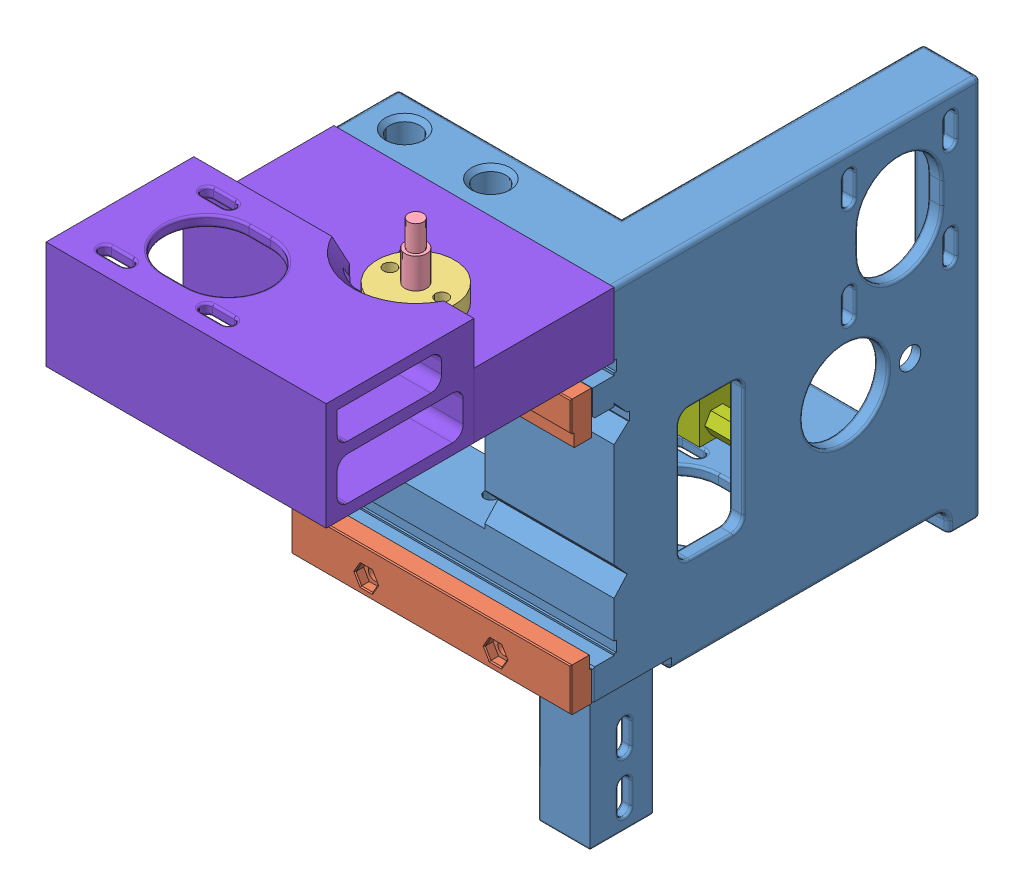
SolidWorks assembly back_carrent_assebly, configuration Default. Lengths in mm.
Overall size (142.93 256 310.81).
9 component instances, 8 part files, 25 mates.
Components (placement in the parent):
- back_integrated-1: back_integrated [Default] at (105.0761 55.2027 88.3003) size (142.93 222 230)
- line_plastic-1: line_plastic [Default] at (184.8997 30.5335 118.1123) x (0 -1 0) z (-1 0 0) size (20 10 130)
- line_plastic-2: line_plastic [Default] at (184.8997 117.3461 148.4883) x (0 1 0) z (-1 0 0) size (20 10 130)
- root_hosder-1: root_hosder [Default] at (144.8997 180.5335 170.3003) x (0.419128 0 -0.907927) z (0 -1 0) size (36 36 28)
- s2-1: s2 [Default] at (144.8997 142.5335 170.3003) x (0.905157 0 0.425078) z (-0.425078 0 0.905157) size (16 64 16)
- key-1: key [Default] at (139.4688 188.0525 167.7498) x (0 1 0) z (0.905157 0 0.425078) size (10 4 6)
- small_sensor-1: small_sensor [Default] at (146.4207 152.5335 148.3003) x (0 -0.945736 0.324935) z (-1 0 0) size (8 8 51)
- injector-1: injector [Default] at (150.9398 10.5335 15.061) x (1 0 0) z (0 1 0) size (75.8 59.7 24.9)
- back_integrated - Copy-1: back_integrated - Copy [Default] at (106.6103 24.7727 88.3003) size (130 50.09 133.58)
Mates (geometry in assembly coordinates):
- Совпадение1: coincident anti-aligned: plane of back_integrated-1 through (105.0761 55.2027 128.3003) normal (0 0 1); plane of line_plastic-1 through (54.8997 30.5335 128.3003) normal (0 0 -1)
- Совпадение2: coincident aligned: plane of back_integrated-1 through (54.8997 10.5335 118.3003) normal (0 -1 0); plane of line_plastic-1 through (54.8997 10.5335 128.3003) normal (0 -1 0)
- Совпадение3: coincident aligned: plane of back_integrated-1 through (184.8997 172.5335 118.3003) normal (1 0 0); plane of line_plastic-1 through (184.8997 30.5335 118.1123) normal (1 0 0)
- Совпадение4: coincident anti-aligned: plane of back_integrated-1 through (105.0761 55.2027 128.3003) normal (0 0 1); plane of line_plastic-2 through (54.8997 137.3461 128.3003) normal (0 0 -1)
- Совпадение5: coincident: plane of back_integrated-1 through (184.8997 137.0335 128.3003) normal (0 1 0); line of line_plastic-2 through (63.7105 137.3461 128.3003) axis (1 0 0)
- Совпадение6: coincident aligned: plane of back_integrated-1 through (184.8997 172.5335 118.3003) normal (1 0 0); plane of line_plastic-2 through (184.8997 117.3461 148.4883) normal (1 0 0)
- Концентричный1: concentric: cylinder of back_integrated-1 through (143.7105 242.8461 170.3003) axis (0 -1 0) radius 8; cylinder of root_hosder-1 through (117.5197 152.5335 151.3003) axis (0 1 0) radius 8
- Совпадение7: coincident anti-aligned: plane of back_integrated-1 through (54.8997 172.5335 118.3003) normal (0 1 0); circle of root_hosder-1
- Концентричный2: concentric: line of assembly; cylinder of assembly; axis of back_integrated-1 through (131.7105 162.8461 170.3003) axis (0 1 0); cylinder of root_hosder-1 through (105.5197 160.5335 151.3003) axis (0 1 0) radius 3
- Концентричный3: concentric: cylinder of root_hosder-1 through (144.8997 172.5335 170.3003) axis (0 1 0) radius 5; cylinder of s2-1 through (144.8997 194.5335 170.3003) axis (0 -1 0) radius 5
- Совпадение8: coincident: circle of root_hosder-1; circle of s2-1
- Совпадение9: coincident anti-aligned: plane of s2-1 through (144.8997 184.5335 170.3003) normal (-0.905157 0 -0.425078); plane of key-1 through (144.8997 184.5335 170.3003) normal (0.905157 0 0.425078)
- Совпадение10: coincident anti-aligned: plane of s2-1 through (134.998 184.5335 167.8598) normal (0.425078 0 -0.905157); plane of key-1 through (144.0496 184.5335 172.1106) normal (-0.425078 0 0.905157)
- Concentric1: concentric: cylinder of back_integrated-1 through (81.9727 152.8461 149.3003) axis (-1 0 0) radius 4.5; cylinder of small_sensor-1 through (99.4207 152.5335 188.5532) axis (1 0 0) radius 4
- Concentric2: concentric: cylinder of back_integrated-1 through (103.7105 152.8461 148.3003) axis (-1 0 0) radius 5; cylinder of small_sensor-1 through (99.4207 152.5335 188.5532) axis (1 0 0) radius 4
- Coincident1: coincident anti-aligned: plane of back_integrated-1 through (105.0761 10.5335 88.3003) normal (0 1 0); plane of injector-1 through (150.9398 10.5335 15.061) normal (0 -1 0)
- Concentric3: concentric anti-aligned: cylinder of s2-1 through (135.8481 184.5335 166.0495) axis (0.905157 0 0.425078) radius 2; cylinder of key-1 through (144.8997 184.5335 170.3003) axis (-0.905157 0 -0.425078) radius 2
- Concentric4: concentric: cylinder of s2-1 through (144.8997 194.5335 170.3003) axis (0 -1 0) radius 5; cylinder of back_integrated - Copy-1 through (124.8997 253.0335 151.3003) axis (0 -1 0) radius 5
- Parallel1: parallel anti-aligned: plane of back_integrated-1 through (105.0761 55.2027 118.3003) normal (0 0 1); plane of back_integrated - Copy-1 through (184.8997 192.5335 118.3003) normal (0 0 -1)
- Coincident5: coincident aligned: plane of back_integrated-1 through (54.8997 172.5335 118.3003) normal (0 1 0); plane of back_integrated - Copy-1 through (54.8997 172.5335 118.3003) normal (0 1 0)
- Concentric5: concentric anti-aligned: cylinder of small_sensor-1 through (99.4207 152.5335 148.3003) axis (1 0 0) radius 4; cylinder of back_integrated - Copy-1 through (104.8997 152.5335 148.3003) axis (-1 0 0) radius 5
- Coincident6: coincident anti-aligned: plane of back_integrated-1 through (105.0761 55.2027 118.3003) normal (0 0 1); plane of back_integrated - Copy-1 through (184.8997 192.5335 118.3003) normal (0 0 -1)
- Coincident7: coincident anti-aligned: plane of back_integrated-1 through (105.0761 55.2027 118.3003) normal (0 0 1); plane of back_integrated - Copy-1 through (184.8997 192.5335 118.3003) normal (0 0 -1)
- Coincident9: coincident aligned: plane of back_integrated-1 through (54.8997 106.5335 118.3003) normal (-1 0 0); plane of back_integrated - Copy-1 through (54.8997 142.5335 118.3003) normal (-1 0 0)
- Concentric7: concentric: cylinder of root_hosder-1 through (144.8997 172.5335 170.3003) axis (0 1 0) radius 18; cylinder of back_integrated - Copy-1 through (144.8997 242.5335 170.3003) axis (0 -1 0) radius 8
